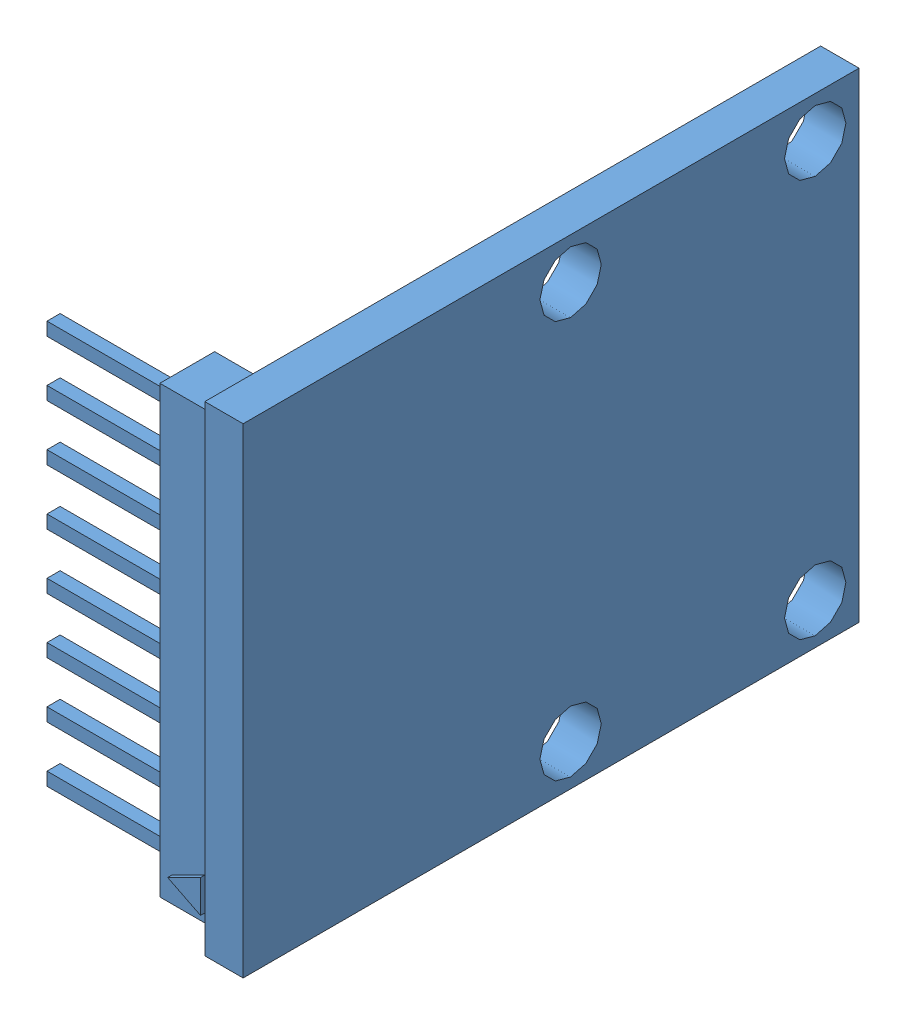
SolidWorks assembly encrAssem, configuration LH. Lengths in mm.
Overall size (18.5 49 36.02).
6 component instances, 4 part files, 18 mates.
Components (placement in the parent):
- encBrkV3-1: encBrkV3 [Default] at origin
- encoder-1: encoder [Default] at (14.5 0 6.47) x (0 -1 0) z (-1 0 0)
- screw_m2x6_course-1: screw_m2x6_course [screw_m2.5] at (12.75 9.075 5.58) x (0 0 1) z (-1 0 0) (hidden)
- screw_m2x6_course-2: screw_m2x6_course [screw_m2.5] at (12.75 -9.075 -5.58) x (0 0 1) z (-1 0 0) (hidden)
- screw_M2.5x6-1: screw_M2.5x6 [6mm] at (-4 31 -7.5) x (0 0 -1) z (1 0 0) (hidden)
- screw_M2.5x6-2: screw_M2.5x6 [6mm] at (-4 31 7.5) x (0 0 -1) z (1 0 0) (hidden)
Mates (geometry in assembly coordinates):
- Coincident1: coincident aligned: plane of encBrkV3-1 through (0 0 0) normal (0 1 0)
- Coincident2: coincident aligned: plane of encBrkV3-1 through (0 0 0) normal (1 0 0)
- Coincident3: coincident aligned: plane of encBrkV3-1 through (0 0 0) normal (0 0 1)
- Coincident4: coincident aligned: line of encoder-1 through (22.6252 0 0) axis (-1 0 0)
- Coincident5: coincident anti-aligned: plane of encBrkV3-1 through (14.5 -13 15.5) normal (-1 0 0); plane of encoder-1 through (14.5 0 6.47) normal (1 0 0)
- Concentric1: concentric anti-aligned: cylinder of encBrkV3-1 through (20.6213 9.075 5.58) axis (-1 0 0) radius 0.75; line of screw_m2x6_course-1 through (10.9447 9.075 5.58) axis (1 0 0)
- Coincident6: coincident anti-aligned: plane of encoder-1 through (12.75 0 6.47) normal (-1 0 0); plane of screw_m2x6_course-1 through (12.75 9.075 5.58) normal (1 0 0)
- Parallel1: parallel aligned: plane of screw_m2x6_course-1 through (12.75 9.075 5.58) normal (0 1 0)
- Concentric2: concentric anti-aligned: cylinder of encBrkV3-1 through (20.6213 -9.075 -5.58) axis (-1 0 0) radius 0.75; line of screw_m2x6_course-2 through (10.9447 -9.075 -5.58) axis (1 0 0)
- Coincident8: coincident anti-aligned: plane of encoder-1 through (12.75 0 6.47) normal (-1 0 0); plane of screw_m2x6_course-2 through (12.75 -9.075 -5.58) normal (1 0 0)
- Parallel2: parallel aligned: plane of screw_m2x6_course-2 through (12.75 -9.075 -5.58) normal (0 1 0)
- Concentric3: concentric anti-aligned: cylinder of encBrkV3-1 through (0 31 -7.5) axis (1 0 0) radius 1.625; line of ScrewM2.5x6-1 through (7.601 31 -7.5) axis (-1 0 0)
- Coincident9: coincident anti-aligned: plane of encBrkV3-1 through (2 31 -7.5) normal (1 0 0); plane of ScrewM2.5x6-1 through (2 31 -7.5) normal (-1 0 0)
- Parallel3: parallel aligned: plane of ScrewM2.5x6-1 through (-4 31 -7.5) normal (0 1 0)
- Concentric4: concentric anti-aligned: cylinder of encBrkV3-1 through (0 31 7.5) axis (1 0 0) radius 1.625; line of ScrewM2.5x6-2 through (7.601 31 7.5) axis (-1 0 0)
- Coincident10: coincident anti-aligned: plane of encBrkV3-1 through (2 31 -7.5) normal (1 0 0); plane of ScrewM2.5x6-2 through (2 31 7.5) normal (-1 0 0)
- Parallel4: parallel aligned: plane of ScrewM2.5x6-2 through (-4 31 7.5) normal (0 1 0)
- LimitAngle1: limit planar angle = 0 rad anti-aligned: plane of encoder-1 through (14.5 0 6.47) normal (0 -1 0)
